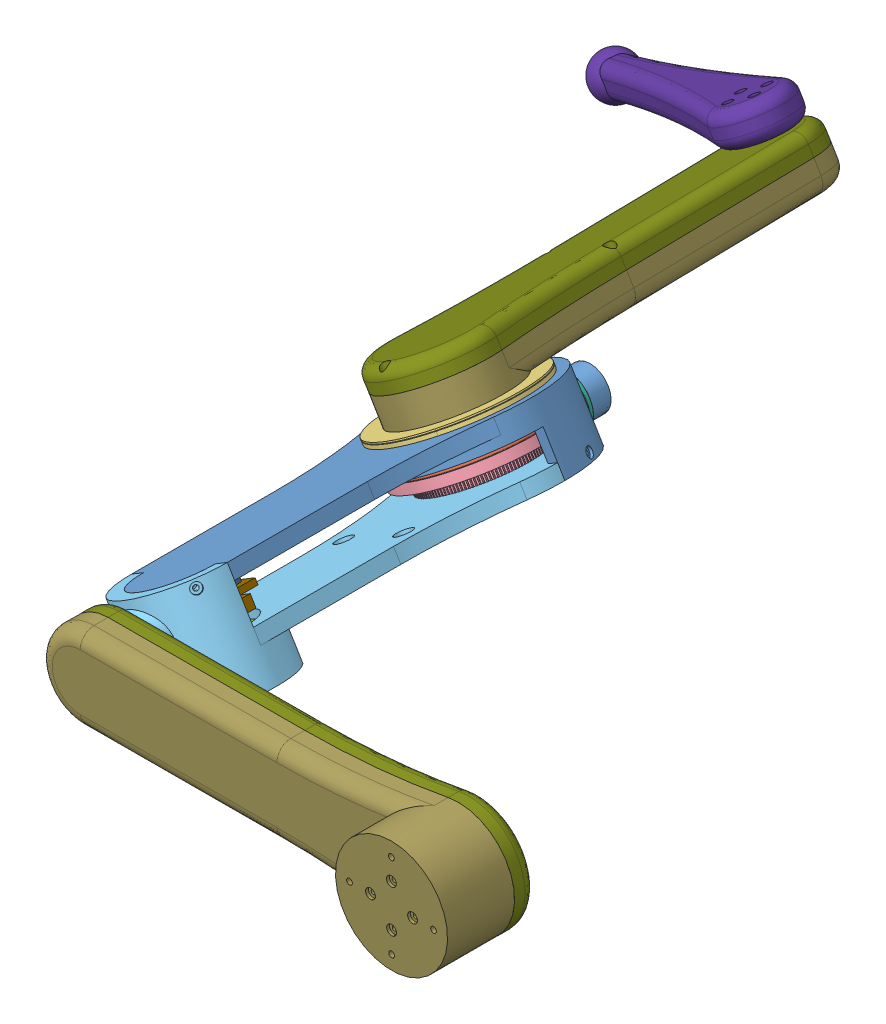
SolidWorks assembly upper leg + shoulder, configuration Default. Lengths in mm.
Overall size (558.05 232.54 690.79).
43 component instances, 17 part files, 6 mates.
Components (placement in the parent):
- shoulder assembly-1: shoulder assembly [Default] at (-92.072 166.3992 5.5935) x (0.518314 -0.85519 0) z (0 0 1) size (74.89 146.9 345) (flexible)
  - body hip-1: body hip [Default] at (46.3831 172.9322 161.1274) size (46 120 310)
  - W_61816_2Z-1: W_61816_2Z [Default] at (56.3831 172.9322 161.1274) x (1 0 0) z (0 -0.196579 0.980488) size (10 124.5 124.5)
  - AXK_80105___AS_80105___AS_80105-1: AXK_80105___AS_80105___AS_80105 [Default] at (45.3831 172.9322 161.1274) x (1 0 0) z (0 0.596292 0.802768) size (6 105 105)
  - shoulder GT2 120-1: shoulder GT2 120 [Default] at (69.1831 172.9322 161.1274) x (0 -0.998538 0.054061) z (0 0.054061 0.998538) size (100 20 100)
  - body hip cover-2: body hip cover [Default] at (82.3831 172.9322 161.1274) size (68.6 120 317)
  - W_61706_2RZ-1: W_61706_2RZ [Default] at (71.8831 172.9322 101.1274) x (0 0 -1) z (0.531643 0.846969 0) size (4 46.12 46.12)
  - W_61706_2RZ-2: W_61706_2RZ [Default] at (82.3831 172.9322 161.1274) size (4 46.12 46.12)
  - MAD5008IPE-1: MAD5008IPE [Default] at (109.9831 172.9322 361.1274) x (0 1 0) z (0 0 1) size (56 29.3 56)
  - GT2 15 Teeth motor-1: GT2 15 Teeth motor [Default] at (82.5677 172.9322 361.1274) x (0 1 0) z (0 0 1) size (24 30 24)
  - hip joint encoder holder-1: hip joint encoder holder [Default] at (70.3831 172.9322 361.1274) x (0 -1 0) z (0 0 -1) size (80 8 46)
  - encoder-1: encoder [Default] at (62.6131 172.9322 361.1274) x (0 -0.973174 0.230072) z (-1 0 0) size (28.79 43.54 9.21)
  - W_617_8-1: W_617_8 [Default] at (53.8831 172.9322 361.1274) x (1 0 0) z (0 -0.003591 0.999994) size (2.5 14.75 14.75)
- lower leg assembly-1: lower leg assembly [Default] at (-50.9689 -47.2639 160.5916) x (-0.046232 -0.028021 -0.998538) z (0.85394 0.517556 -0.054061) size (357.54 90.3 290.58) (flexible)
  - upper limb assembly-1: upper limb assembly [Default] at (-19.8745 -6.1915 12.8481) size (322.61 71.8 80) (flexible)
    - upper limb v4-1: upper limb v4 [Default] at (0.3187 172.8353 234.9828) size (320 47.8 80)
    - MAD5008IPE-1: MAD5008IPE [Default] at (0.3187 147.0353 234.9828) x (0.56755 0 -0.823339) z (0.823339 0 0.56755) size (56 29.3 56)
    - GT2 15 Teeth motor-1: GT2 15 Teeth motor [Default] at (0.3187 174.4507 234.9828) x (0.56755 0 -0.823339) z (0.823339 0 0.56755) size (24 30 24)
    - 15_45 pulley-1: 15_45 pulley [Default] at (100.957 199.9066 228.2835) x (-0.188791 0 0.982017) z (0.982017 0 0.188791) size (34 30.5 34)
    - W_617_8-1: W_617_8 [Default] at (109.9187 170.3353 234.9828) x (0 1 0) z (0.777212 0 0.629238) size (2.5 14.75 14.75)
    - W_61706_2RZ-1: W_61706_2RZ [Default] at (250.3187 174.3353 234.9828) x (0 -1 0) z (0.706264 0 0.707949) size (4 46.12 46.12)
    - encoder-1: encoder [Default] at (0.3187 191.6053 234.9828) x (0.325666 0 -0.945485) z (0 1 0) size (28.79 43.54 9.21)
    - encoder holder-1: encoder holder [Default] at (0.3187 182.8353 234.9828) x (0 0 -1) z (1 0 0) size (70 5 40.98)
    - knee joint 45T-1: knee joint 45T [Default] at (250.3187 183.8353 234.9828) x (0.418723 0 -0.908114) z (0.908114 0 0.418723) size (34 41.5 34)
    - upper limb cover v4-1: upper limb cover v4 [Default] at (0.3187 198.3353 234.9828) x (1 0 0) z (0 0 -1) size (320 15.79 80)
    - W_617_8-2: W_617_8 [Default] at (109.9187 198.3353 234.9828) x (0 1 0) z (0.777212 0 0.629238) size (2.5 14.75 14.75)
    - W_617_8-3: W_617_8 [Default] at (0.3187 198.3353 234.9828) x (0 1 0) z (0.914217 0 -0.405224) size (2.5 14.75 14.75)
    - W_61706_2RZ-2: W_61706_2RZ [Default] at (250.3187 200.8353 234.9828) x (0 -1 0) z (0.706264 0 0.707949) size (4 46.12 46.12)
  - lower limb-1: lower limb [Default] at (230.4442 205.6438 247.8309) x (0.908114 0 0.418723) z (0 -1 0) size (50 275 43.5)
- upper limb assembly-1: upper limb assembly [Default] at (342.7484 430.228 618.5561) x (-0.999996 -0.002746 0) z (0.002746 -0.999996 0) size (322.06 71.8 80) (flexible)
  - upper limb v4-1: upper limb v4 [Default] at (0.3187 172.8353 234.9828) size (320 47.8 80)
  - MAD5008IPE-1: MAD5008IPE [Default] at (0.3187 147.0353 234.9828) x (0.76432 0 -0.644837) z (0.644837 0 0.76432) size (56 29.3 56)
  - GT2 15 Teeth motor-1: GT2 15 Teeth motor [Default] at (0.3187 174.4507 234.9828) x (0.76432 0 -0.644837) z (0.644837 0 0.76432) size (24 30 24)
  - 15_45 pulley-1: 15_45 pulley [Default] at (114.854 199.9066 224.9411) x (-0.999988 0 -0.004797) z (-0.004797 0 0.999988) size (34 30.5 34)
  - W_617_8-1: W_617_8 [Default] at (109.9187 170.3353 234.9828) x (0 1 0) z (-0.475418 0 0.87976) size (2.5 14.75 14.75)
  - W_61706_2RZ-1: W_61706_2RZ [Default] at (250.3187 174.3353 234.9828) x (0 -1 0) z (-0.565843 0 0.824513) size (4 46.12 46.12)
  - encoder-1: encoder [Default] at (0.3187 191.6053 234.9828) x (-0.01184 0 -0.99993) z (0 1 0) size (28.79 43.54 9.21) (hidden)
  - encoder holder-1: encoder holder [Default] at (0.3187 182.8353 234.9828) x (0 0 -1) z (1 0 0) size (70 5 40.98)
  - knee joint 45T-1: knee joint 45T [Default] at (250.3187 183.8353 234.9828) x (0.515963 0 -0.856611) z (0.856611 0 0.515963) size (34 41.5 34)
  - upper limb cover v4-1: upper limb cover v4 [Default] at (0.3187 198.3353 234.9828) x (1 0 0) z (0 0 -1) size (320 15.79 80)
  - W_617_8-2: W_617_8 [Default] at (109.9187 198.3353 234.9828) x (0 1 0) z (-0.475418 0 0.87976) size (2.5 14.75 14.75)
  - W_617_8-3: W_617_8 [Default] at (0.3187 198.3353 234.9828) x (0 1 0) z (0.566587 0 0.824002) size (2.5 14.75 14.75)
  - W_61706_2RZ-2: W_61706_2RZ [Default] at (250.3187 200.8353 234.9828) x (0 -1 0) z (-0.565843 0 0.824513) size (4 46.12 46.12)
Mates (geometry in assembly coordinates):
- Concentric1: concentric: cylinder of shoulder assembly-1/W_61816_2Z-1 through (110.9578 165.0545 166.7208) axis (0.518314 -0.85519 0) radius 40; cylinder of lower leg assembly-1/upper limb assembly-1/upper limb v4-1 through (67.4195 236.8905 166.7208) axis (0.518314 -0.85519 0) radius 40
- Concentric2: concentric: cylinder of shoulder assembly-1/shoulder GT2 120-1 through (88.8383 198.4215 136.7647) axis (0.518314 -0.85519 0) radius 1.7; cylinder of lower leg assembly-1/upper limb assembly-1/upper limb v4-1 through (87.698 200.3029 136.7647) axis (0.518314 -0.85519 0) radius 2.05
- Coincident1: coincident: plane of shoulder assembly-1/shoulder GT2 120-1 through (92.1949 196.0124 166.7208) normal (-0.518314 0.85519 0); plane of lower leg assembly-1/upper limb assembly-1/upper limb v4-1 through (92.1949 196.0124 166.7208) normal (0.518314 -0.85519 0)
- Coincident5: coincident: plane of shoulder assembly-1/body hip cover-2 through (82.7747 197.0852 431.7208) normal (-0.85519 -0.518314 0); plane of upper limb assembly-1/knee joint 45T-1 through (90.5494 184.2573 431.7208) normal (0.85519 0.518314 0)
- Coincident6: coincident: plane of shoulder assembly-1/body hip cover-2 through (82.7747 197.0852 431.7208) normal (-0.518314 0.85519 0); plane of upper limb assembly-1/knee joint 45T-1 through (82.7747 197.0852 431.7208) normal (0.518314 -0.85519 0)
- Coincident7: coincident: plane of shoulder assembly-1/body hip cover-2 through (93.076 194.5586 406.7208) normal (0 0 1); plane of upper limb assembly-1/knee joint 45T-1 through (93.076 194.5586 406.7208) normal (0 0 -1)
